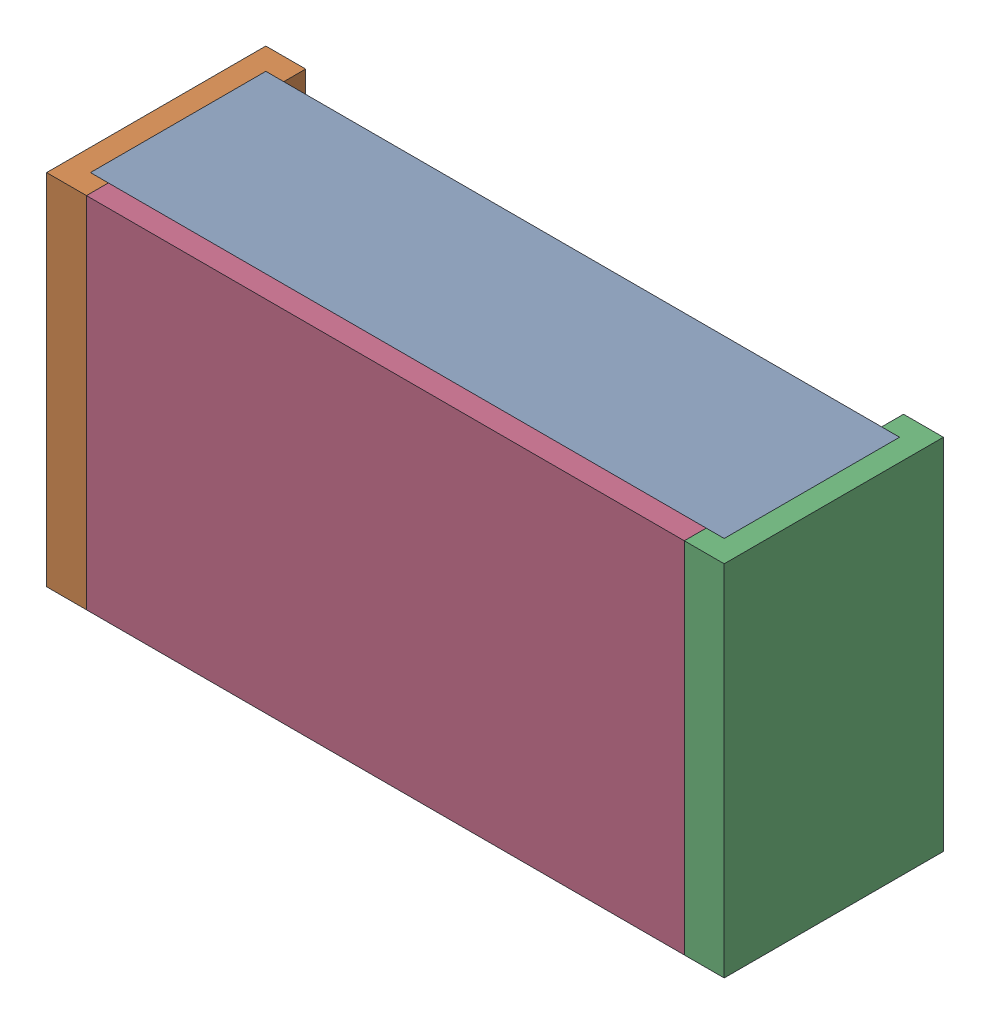
SolidWorks assembly 6019289920, configuration Default. Lengths in mm.
Overall size (1.7 0.9 0.55).
6 component instances, 3 part files, 0 mates.
Components (placement in the parent):
- Mid_Body_2-1: Mid_Body_2 [Default] at (-0.85 -0.45 0) size (1.59 0.9 0.44)
- Terminal_2-1: Terminal_2 [Default] at (-0.85 -0.45 0) size (0.1 0.9 0.55)
  - Open CASCADE STEP translator 6.8 15.2.1_2-1: Open CASCADE STEP translator 6.8 15.2.1_2 [Default] at origin size (0.1 0.9 0.55)
- Terminal_2-2: Terminal_2 [Default] at (0.85 0.45 0) x (-1 0 0) z (0 0 1) size (0.1 0.9 0.55)
  - Open CASCADE STEP translator 6.8 15.2.1_2-1: Open CASCADE STEP translator 6.8 15.2.1_2 [Default] at origin size (0.1 0.9 0.55)
- Mark_2-1: Mark_2 [Default] at (-0.75 -0.45 0.495) size (1.5 0.9 0.06)
